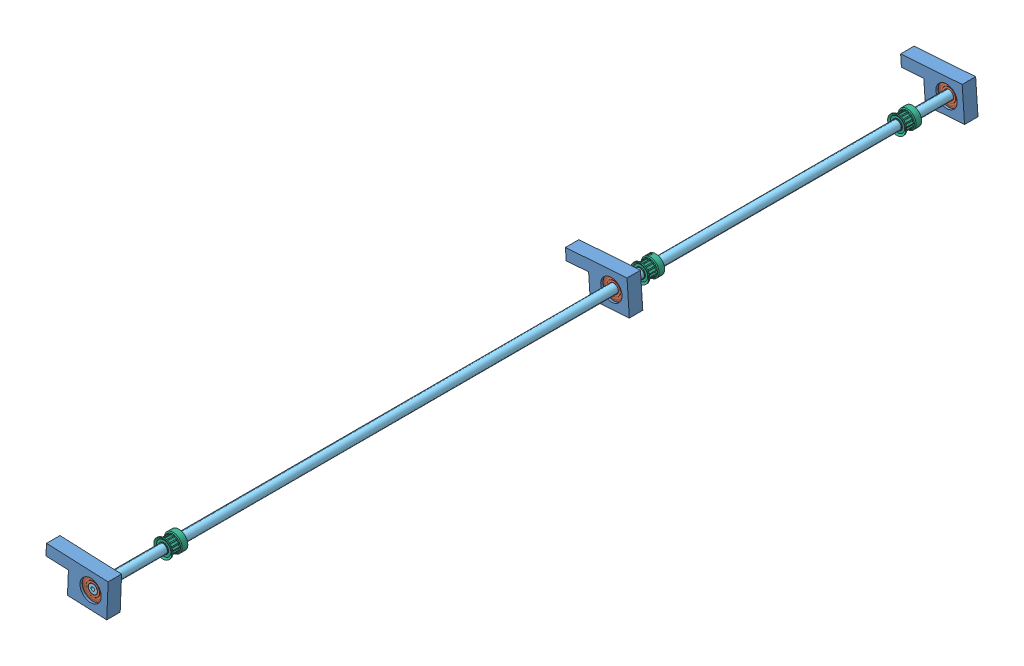
SolidWorks assembly drive_shaft_assembled, configuration Standard. Lengths in mm.
Overall size (56.96 34.42 775).
61 component instances, 7 part files, 9 mates.
Components (placement in the parent):
- Lagerbock_assembled-1: Lagerbock_assembled [Standard] at (-81.1418 -2.5498 145.8745) x (0.069767 -0.997563 0) z (0 0 1) size (30 55 12)
  - Lagerbock-1: Lagerbock [Standard] at (0.8863 -1.2135 34) size (30 55 12)
  - 608-2Z-1: 608-2Z [Standard] at (0.8863 -1.2135 44) x (0 0 -1) z (1 0 0) size (7 22 22)
    - 608-2Z_PART1-1: 608-2Z_PART1 [Standard] at origin size (7 19.2 19.2)
    - 608-2Z_PART2-1: 608-2Z_PART2 [Standard] at origin size (7 22 22)
    - 608-2Z_PART3-1: 608-2Z_PART3 [Standard] at origin size (3.97 3.97 3.97)
    - 608-2Z_PART3-2: 608-2Z_PART3 [Standard] x (1 0 0) z (0 0.781831 0.62349) size (3.97 3.97 3.97)
    - 608-2Z_PART3-3: 608-2Z_PART3 [Standard] x (1 0 0) z (0 0.974928 -0.222521) size (3.97 3.97 3.97)
    - 608-2Z_PART3-4: 608-2Z_PART3 [Standard] x (1 0 0) z (0 0.433884 -0.900969) size (3.97 3.97 3.97)
    - 608-2Z_PART3-5: 608-2Z_PART3 [Standard] x (1 0 0) z (0 -0.433884 -0.900969) size (3.97 3.97 3.97)
    - 608-2Z_PART3-6: 608-2Z_PART3 [Standard] x (1 0 0) z (0 -0.974928 -0.222521) size (3.97 3.97 3.97)
    - 608-2Z_PART3-7: 608-2Z_PART3 [Standard] x (1 0 0) z (0 -0.781831 0.62349) size (3.97 3.97 3.97)
    - 608-2Z_PART4-1: 608-2Z_PART4 [Standard] at origin
    - 608-2Z_PART4-2: 608-2Z_PART4 [Standard] x (1 0 0) z (0 0.781831 0.62349)
    - 608-2Z_PART4-3: 608-2Z_PART4 [Standard] x (1 0 0) z (0 0.974928 -0.222521)
    - 608-2Z_PART4-4: 608-2Z_PART4 [Standard] x (1 0 0) z (0 0.433884 -0.900969)
    - 608-2Z_PART4-5: 608-2Z_PART4 [Standard] x (1 0 0) z (0 -0.433884 -0.900969)
    - 608-2Z_PART4-6: 608-2Z_PART4 [Standard] x (1 0 0) z (0 -0.974928 -0.222521)
    - 608-2Z_PART4-7: 608-2Z_PART4 [Standard] x (1 0 0) z (0 -0.781831 0.62349)
- Lagerbock_assembled-2: Lagerbock_assembled [Standard] at (-81.0409 -2.684 610.0818) x (-0.041961 -0.999119 0) z (0 0 1) size (30 55 12)
  - Lagerbock-1: Lagerbock [Standard] at (0.8863 -1.2135 34) size (30 55 12)
  - 608-2Z-1: 608-2Z [Standard] at (0.8863 -1.2135 44) x (0 0 -1) z (1 0 0) size (7 22 22)
    - 608-2Z_PART1-1: 608-2Z_PART1 [Standard] at origin size (7 19.2 19.2)
    - 608-2Z_PART2-1: 608-2Z_PART2 [Standard] at origin size (7 22 22)
    - 608-2Z_PART3-1: 608-2Z_PART3 [Standard] at origin size (3.97 3.97 3.97)
    - 608-2Z_PART3-2: 608-2Z_PART3 [Standard] x (1 0 0) z (0 0.781831 0.62349) size (3.97 3.97 3.97)
    - 608-2Z_PART3-3: 608-2Z_PART3 [Standard] x (1 0 0) z (0 0.974928 -0.222521) size (3.97 3.97 3.97)
    - 608-2Z_PART3-4: 608-2Z_PART3 [Standard] x (1 0 0) z (0 0.433884 -0.900969) size (3.97 3.97 3.97)
    - 608-2Z_PART3-5: 608-2Z_PART3 [Standard] x (1 0 0) z (0 -0.433884 -0.900969) size (3.97 3.97 3.97)
    - 608-2Z_PART3-6: 608-2Z_PART3 [Standard] x (1 0 0) z (0 -0.974928 -0.222521) size (3.97 3.97 3.97)
    - 608-2Z_PART3-7: 608-2Z_PART3 [Standard] x (1 0 0) z (0 -0.781831 0.62349) size (3.97 3.97 3.97)
    - 608-2Z_PART4-1: 608-2Z_PART4 [Standard] at origin
    - 608-2Z_PART4-2: 608-2Z_PART4 [Standard] x (1 0 0) z (0 0.781831 0.62349)
    - 608-2Z_PART4-3: 608-2Z_PART4 [Standard] x (1 0 0) z (0 0.974928 -0.222521)
    - 608-2Z_PART4-4: 608-2Z_PART4 [Standard] x (1 0 0) z (0 0.433884 -0.900969)
    - 608-2Z_PART4-5: 608-2Z_PART4 [Standard] x (1 0 0) z (0 -0.433884 -0.900969)
    - 608-2Z_PART4-6: 608-2Z_PART4 [Standard] x (1 0 0) z (0 -0.974928 -0.222521)
    - 608-2Z_PART4-7: 608-2Z_PART4 [Standard] x (1 0 0) z (0 -0.781831 0.62349)
- drive_shaft-1: drive_shaft [Standard] at (-82.2905 -3.5186 -112.9182) x (0 0 -1) z (0.760817 0.648966 0) size (770 8 8)
- Pulley 1-1: Pulley 1 [Default] at (-82.2905 -3.5186 -77.181) x (0 0 1) z (-1 0 0) size (14.8 16 16)
- Pulley 1-2: Pulley 1 [Default] at (-82.2905 -3.5186 151.8444) x (0 0 1) z (-0.382013 0.924157 0) size (14.8 16 16)
- Pulley 1-3: Pulley 1 [Default] at (-82.2905 -3.5186 576.9456) x (0 0 1) z (-1 0 0) size (14.8 16 16)
- Lagerbock_assembled-3: Lagerbock_assembled [Standard] at (-81.1418 -2.5498 -152.9182) x (0.069767 -0.997563 0) z (0 0 1) size (30 55 12)
  - Lagerbock-1: Lagerbock [Standard] at (0.8863 -1.2135 34) size (30 55 12)
  - 608-2Z-1: 608-2Z [Standard] at (0.8863 -1.2135 44) x (0 0 -1) z (1 0 0) size (7 22 22)
    - 608-2Z_PART1-1: 608-2Z_PART1 [Standard] at origin size (7 19.2 19.2)
    - 608-2Z_PART2-1: 608-2Z_PART2 [Standard] at origin size (7 22 22)
    - 608-2Z_PART3-1: 608-2Z_PART3 [Standard] at origin size (3.97 3.97 3.97)
    - 608-2Z_PART3-2: 608-2Z_PART3 [Standard] x (1 0 0) z (0 0.781831 0.62349) size (3.97 3.97 3.97)
    - 608-2Z_PART3-3: 608-2Z_PART3 [Standard] x (1 0 0) z (0 0.974928 -0.222521) size (3.97 3.97 3.97)
    - 608-2Z_PART3-4: 608-2Z_PART3 [Standard] x (1 0 0) z (0 0.433884 -0.900969) size (3.97 3.97 3.97)
    - 608-2Z_PART3-5: 608-2Z_PART3 [Standard] x (1 0 0) z (0 -0.433884 -0.900969) size (3.97 3.97 3.97)
    - 608-2Z_PART3-6: 608-2Z_PART3 [Standard] x (1 0 0) z (0 -0.974928 -0.222521) size (3.97 3.97 3.97)
    - 608-2Z_PART3-7: 608-2Z_PART3 [Standard] x (1 0 0) z (0 -0.781831 0.62349) size (3.97 3.97 3.97)
    - 608-2Z_PART4-1: 608-2Z_PART4 [Standard] at origin
    - 608-2Z_PART4-2: 608-2Z_PART4 [Standard] x (1 0 0) z (0 0.781831 0.62349)
    - 608-2Z_PART4-3: 608-2Z_PART4 [Standard] x (1 0 0) z (0 0.974928 -0.222521)
    - 608-2Z_PART4-4: 608-2Z_PART4 [Standard] x (1 0 0) z (0 0.433884 -0.900969)
    - 608-2Z_PART4-5: 608-2Z_PART4 [Standard] x (1 0 0) z (0 -0.433884 -0.900969)
    - 608-2Z_PART4-6: 608-2Z_PART4 [Standard] x (1 0 0) z (0 -0.974928 -0.222521)
    - 608-2Z_PART4-7: 608-2Z_PART4 [Standard] x (1 0 0) z (0 -0.781831 0.62349)
Mates (geometry in assembly coordinates):
- Konzentrisch1: concentric anti-aligned: cylinder of Lagerbock_assembled-1/608-2Z-1/608-2Z_PART1-1 through (-82.2905 -3.5186 139.8745) axis (0 0 1) radius 4; cylinder of drive_shaft-1 through (-82.2905 -3.5186 -112.9182) axis (0 0 -1) radius 4
- Konzentrisch3: concentric anti-aligned: cylinder of Lagerbock_assembled-2/608-2Z-1/608-2Z_PART1-1 through (-82.2905 -3.5186 604.0818) axis (0 0 1) radius 4; cylinder of drive_shaft-1 through (-82.2905 -3.5186 -112.9182) axis (0 0 -1) radius 4
- Deckungsgleich7: coincident aligned: plane of Lagerbock_assembled-2/608-2Z-1/608-2Z_PART1-1 through (-76.3208 -3.7693 654.0818) normal (0 0 1); plane of drive_shaft-1 through (-83.3288 -2.3013 654.0818) normal (0 0 1)
- Konzentrisch4: concentric anti-aligned: cylinder of drive_shaft-1 through (-82.2905 -3.5186 -112.9182) axis (0 0 -1) radius 4; cylinder of Pulley 1-1 through (-82.2905 -3.5186 -77.181) axis (0 0 1) radius 2.5
- Konzentrisch5: concentric anti-aligned: cylinder of drive_shaft-1 through (-82.2905 -3.5186 -112.9182) axis (0 0 -1) radius 4; cylinder of Pulley 1-3 through (-82.2905 -3.5186 576.9456) axis (0 0 1) radius 2.5
- Konzentrisch6: concentric anti-aligned: cylinder of drive_shaft-1 through (-82.2905 -3.5186 -112.9182) axis (0 0 -1) radius 4; cylinder of Pulley 1-2 through (-82.2905 -3.5186 151.8444) axis (0 0 1) radius 2.5
- Konzentrisch7: concentric anti-aligned: cylinder of drive_shaft-1 through (-82.2905 -3.5186 -112.9182) axis (0 0 -1) radius 4; cylinder of Lagerbock_assembled-3/608-2Z-1/608-2Z_PART1-1 through (-82.2905 -3.5186 -158.9182) axis (0 0 1) radius 4
- Deckungsgleich8: coincident aligned: plane of Lagerbock_assembled-1/Lagerbock-1 through (-66.2805 -17.4355 191.8745) normal (0.997563 0.069767 0); plane of Lagerbock_assembled-3/Lagerbock-1 through (-66.2805 -17.4355 -106.9182) normal (0.997563 0.069767 0)
- Deckungsgleich9: coincident aligned: plane of drive_shaft-1 through (-83.3288 -2.3013 -115.9182) normal (0 0 -1); plane of Lagerbock_assembled-3/608-2Z-1/608-2Z_PART1-1 through (-78.001 -3.2186 -115.9182) normal (0 0 -1)
